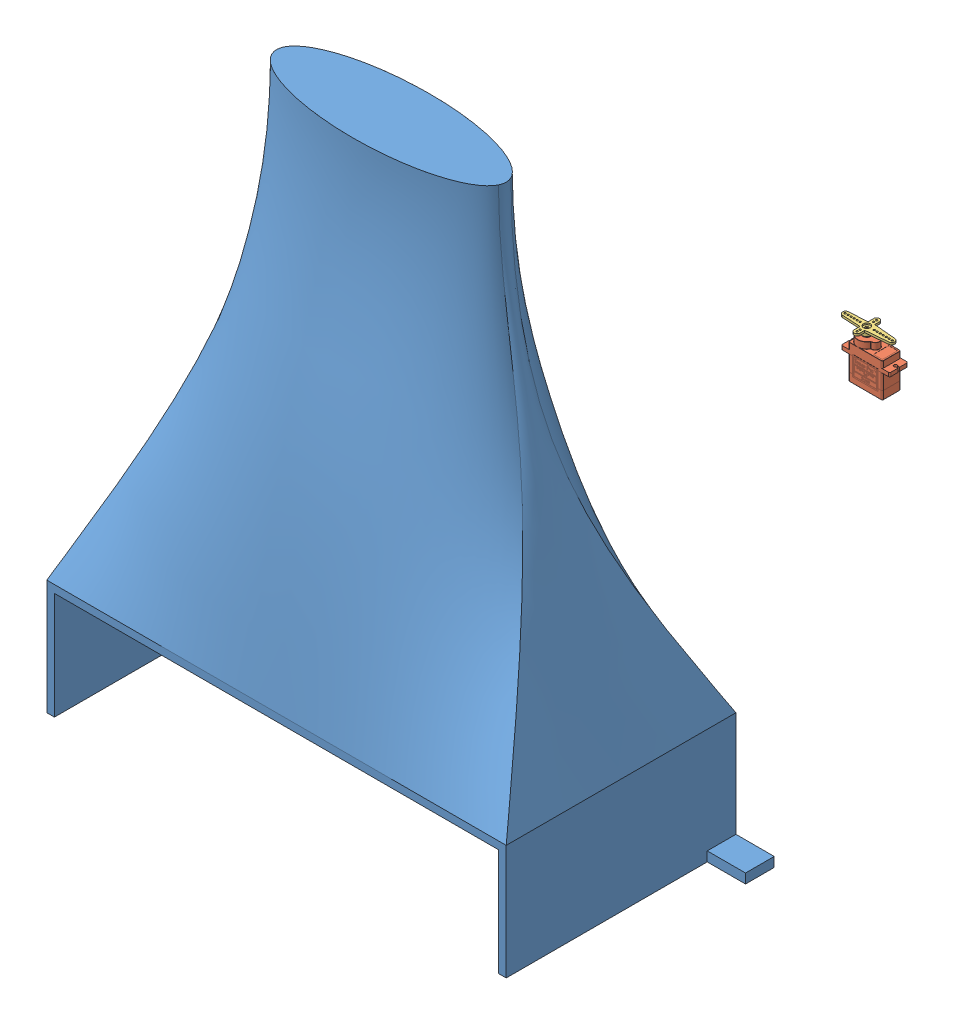
SolidWorks assembly arm_Assembly, configuration Défaut. Lengths in mm.
Overall size (362.43 381 236.55).
4 component instances, 3 part files, 0 mates.
Components (placement in the parent):
- Bras-1: Bras [Défaut] at (-85.1551 148.9671 381.0005) size (355.6 381 152.4)
- SG90 - Micro Servo Assembly Socle-1: SG90 - Micro Servo Assembly Socle [Default] at (83.4261 13.0018 228.9971) size (37.25 31.75 16.7)
  - SG90 - Micro Servo 9g - Tower Pro.1-2: SG90 - Micro Servo 9g - Tower Pro.1 [Peça] at origin size (32.1 29.95 12.4)
  - SG90 - Micro Servo 9g - Tower Pro.4-1: SG90 - Micro Servo 9g - Tower Pro.4 [Peça] at (-5.15 21.1 0) size (34.5 3.8 16.7)
